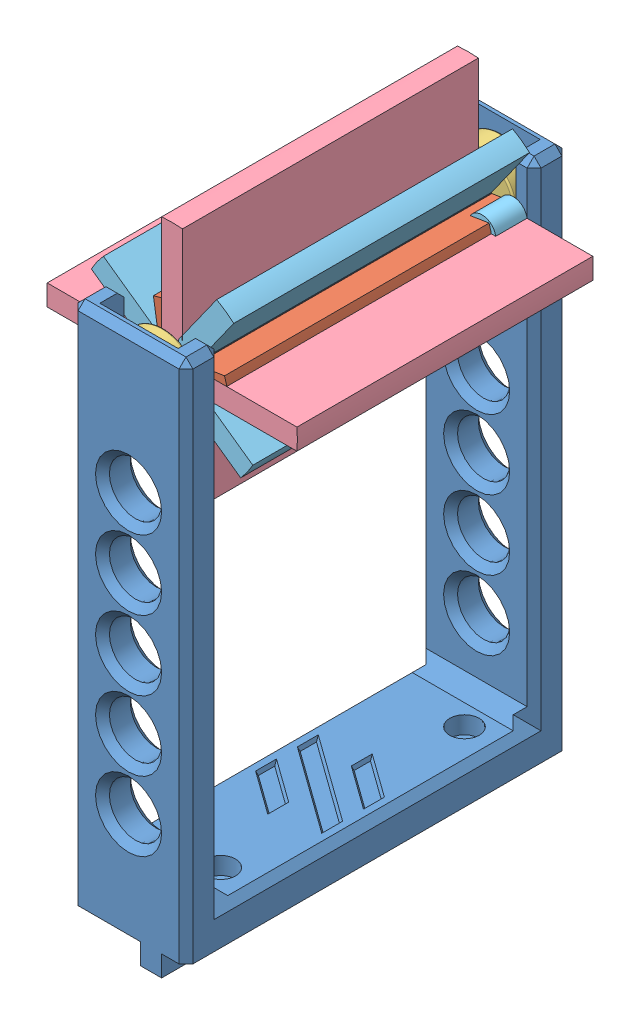
SolidWorks assembly FilamentRollers, configuration Default. Lengths in mm.
Overall size (73.91 177.96 110).
6 component instances, 5 part files, 10 mates.
Components (placement in the parent):
- SpoolHolderV4-1: SpoolHolderV4 [Default] at (14.8823 -82.5447 -26.0413) size (33 156 110)
- ClearRoll32x85-1: ClearRoll32x85 [Default] at (31.3823 52.4553 -13.5413) x (-0.988354 -0.152173 0) z (0 0 1) size (32 32 85)
- Bearing22x7x8-1: Bearing22x7x8 [Default] at (31.3823 52.4553 -23.0413) size (22 22 7)
- Bearing22x7x8-2: Bearing22x7x8 [Default] at (31.3823 52.4553 73.9587) size (22 22 7)
- ClearRoll72x85-1: ClearRoll72x85 [Default] at (31.3823 52.4553 -13.5413) size (72 72 85)
- ClearRoll53x85-1: ClearRoll53x85 [Default] at (31.3823 52.4553 -13.5413) x (0.57982 0.814745 0) z (0 0 1) size (53 53 85)
Mates (geometry in assembly coordinates):
- Coincident2: coincident anti-aligned: plane of SpoolHolderV4-1 through (31.3823 52.4553 -23.0413) normal (0 0 1); plane of Bearing22x7x8-1 through (31.3823 52.4553 -23.0413) normal (0 0 -1)
- Concentric2: concentric anti-aligned: cylinder of SpoolHolderV4-1 through (31.3823 52.4553 -23.0413) axis (0 0 1) radius 11.25; cylinder of Bearing22x7x8-1 through (31.3823 52.4553 -16.0413) axis (0 0 -1) radius 11
- Coincident3: coincident anti-aligned: plane of SpoolHolderV4-1 through (31.3823 52.4553 80.9587) normal (0 0 -1); plane of Bearing22x7x8-2 through (31.3823 52.4553 80.9587) normal (0 0 1)
- Concentric3: concentric aligned: cylinder of SpoolHolderV4-1 through (31.3823 52.4553 80.9587) axis (0 0 -1) radius 11.25; cylinder of Bearing22x7x8-2 through (31.3823 52.4553 80.9587) axis (0 0 -1) radius 11
- Concentric4: concentric aligned: cylinder of ClearRoll32x85-1 through (31.3823 52.4553 -8.5413) axis (0 0 -1) radius 4; cylinder of Bearing22x7x8-1 through (31.3823 52.4553 -16.0413) axis (0 0 -1) radius 4.075
- Distance1: distance = 2.5 mm anti-aligned: plane of ClearRoll32x85-1 through (31.3823 52.4553 -13.5413) normal (0 0 -1); plane of Bearing22x7x8-1 through (31.3823 52.4553 -16.0413) normal (0 0 1)
- Concentric5: concentric aligned: cylinder of Bearing22x7x8-1 through (31.3823 52.4553 -16.0413) axis (0 0 -1) radius 4.075; cylinder of ClearRoll53x85-1 through (31.3823 52.4553 -8.5413) axis (0 0 -1) radius 4
- Distance2: distance = 2.5 mm anti-aligned: plane of ClearRoll53x85-1 through (31.3823 52.4553 -13.5413) normal (0 0 -1); plane of Bearing22x7x8-1 through (31.3823 52.4553 -16.0413) normal (0 0 1)
- Distance3: distance = 2.5 mm anti-aligned: plane of ClearRoll72x85-1 through (31.3823 52.4553 -13.5413) normal (0 0 -1); plane of Bearing22x7x8-1 through (31.3823 52.4553 -16.0413) normal (0 0 1)
- Concentric6: concentric aligned: cylinder of Bearing22x7x8-1 through (31.3823 52.4553 -16.0413) axis (0 0 -1) radius 4.075; cylinder of ClearRoll72x85-1 through (31.3823 52.4553 -8.5413) axis (0 0 -1) radius 4
